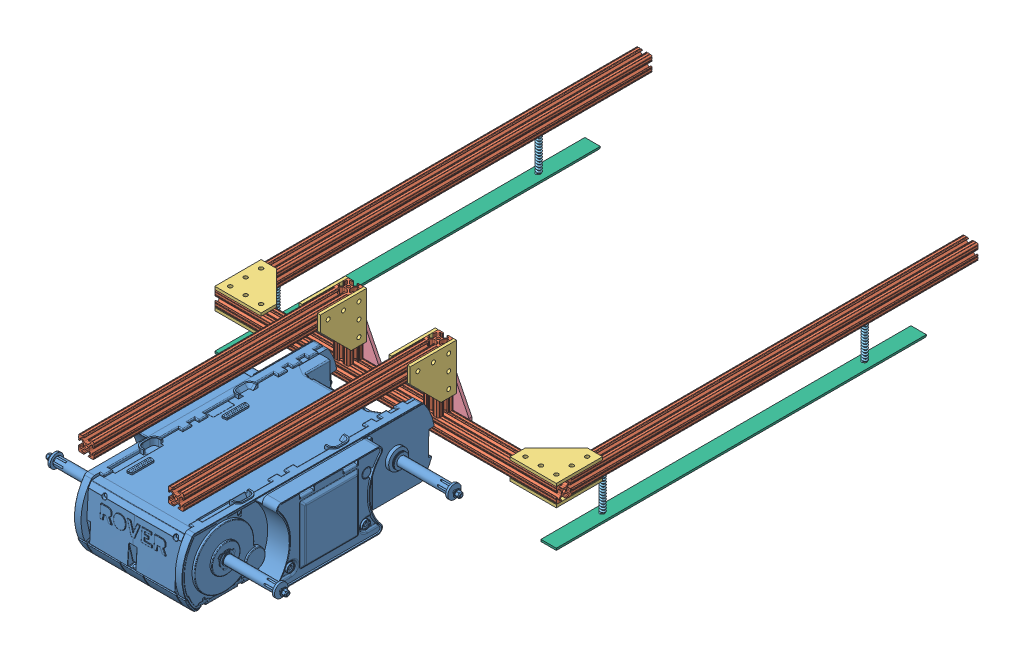
SolidWorks assembly BotAssembly.12.26.2020, configuration Default. Lengths in mm.
Overall size (562.5 192.5 1123.3).
26 component instances, 6 part files, 55 mates.
Components (placement in the parent):
- Rover Body-1: Rover Body [Default] at (125.1119 198.811 488.8206) size (400.01 131.58 418.13)
- Top Rail-10: Top Rail [Bot Mounting] at (51.1531 303.611 339.8706) size (25.4 25.4 419.1)
- Top Rail-12: Top Rail [Bot Mounting] at (199.0708 303.611 339.8706) size (25.4 25.4 419.1)
- Top Rail-13: Top Rail [Vertical Rail] at (51.1531 265.511 117.6206) x (1 0 0) z (0 1 0) size (25.4 25.4 101.6)
- Top Rail-15: Top Rail [Vertical Rail] at (199.0708 265.511 117.6206) x (1 0 0) z (0 1 0) size (25.4 25.4 101.6)
- Top Rail-14: Top Rail [Top Rail Base 16.3] at (125.1119 202.011 117.6206) x (0 1 0) z (-1 0 0) size (25.4 25.4 562.5)
- 47065T267_ALUMINUM T-SLOTTED FRAMING EXTRUSION-13: 47065T267_ALUMINUM T-SLOTTED FRAMING EXTRUSION [47065T267] at (36.0718 316.311 104.9206) x (0 0 1) z (1 0 0) size (76.2 76.2 4.76)
- 47065T267_ALUMINUM T-SLOTTED FRAMING EXTRUSION-9: 47065T267_ALUMINUM T-SLOTTED FRAMING EXTRUSION [47065T267] at (214.152 316.311 104.9206) x (0 0 1) z (1 0 0) size (76.2 76.2 4.76)
- Top Rail-11: Top Rail [Side Rail] at (393.6623 202.011 -229.71) size (25.4 25.4 669.26)
- Top Rail-16: Top Rail [Side Rail] at (-143.4384 202.011 -229.71) size (25.4 25.4 669.26)
- 47065T267_ALUMINUM T-SLOTTED FRAMING EXTRUSION-15: 47065T267_ALUMINUM T-SLOTTED FRAMING EXTRUSION [47065T267] at (406.3623 217.0923 130.3206) x (0 0 -1) z (0 1 0) size (76.2 76.2 4.76)
- 47065T267_ALUMINUM T-SLOTTED FRAMING EXTRUSION-14: 47065T267_ALUMINUM T-SLOTTED FRAMING EXTRUSION [47065T267] at (-156.1384 217.0923 130.3206) x (1 0 0) z (0 1 0) size (76.2 76.2 4.76)
- 47065T278_ALUMINUM T-SLOTTED FRAMING EXTRUSION-3: 47065T278_ALUMINUM T-SLOTTED FRAMING EXTRUSION [47065T278] at (160.9708 189.311 102.5393) size (76.2 76.2 4.76)
- 47065T278_ALUMINUM T-SLOTTED FRAMING EXTRUSION-4: 47065T278_ALUMINUM T-SLOTTED FRAMING EXTRUSION [47065T278] at (13.0531 189.311 102.5393) size (76.2 76.2 4.76)
- 47065T267_ALUMINUM T-SLOTTED FRAMING EXTRUSION-10: 47065T267_ALUMINUM T-SLOTTED FRAMING EXTRUSION [47065T267] at (406.3623 186.9298 130.3206) x (0 0 -1) z (0 1 0) size (76.2 76.2 4.76)
- 47065T267_ALUMINUM T-SLOTTED FRAMING EXTRUSION-12: 47065T267_ALUMINUM T-SLOTTED FRAMING EXTRUSION [47065T267] at (-156.1384 186.9298 130.3206) x (1 0 0) z (0 1 0) size (76.2 76.2 4.76)
- 47065T267_ALUMINUM T-SLOTTED FRAMING EXTRUSION-11: 47065T267_ALUMINUM T-SLOTTED FRAMING EXTRUSION [47065T267] at (66.2343 316.311 104.9206) x (0 0 1) z (1 0 0) size (76.2 76.2 4.76)
- 47065T267_ALUMINUM T-SLOTTED FRAMING EXTRUSION-16: 47065T267_ALUMINUM T-SLOTTED FRAMING EXTRUSION [47065T267] at (183.9895 316.311 104.9206) x (0 0 1) z (1 0 0) size (76.2 76.2 4.76)
- SkidAssembly.12.26.2020-1: SkidAssembly.12.26.2020 [Default] at (-122.0534 148.8468 -277.5557) x (-1 0 0) z (0 0 -1) size (25.4 67.77 609.6)
  - Rudimentary Spring-1: Rudimentary Spring [Default] at (21.385 -21.8607 112.8238) x (0.707107 0 0.707107) z (-0.707107 0 0.707107) size (9.2 66.86 9.2)
  - Skid Plate-1: Skid Plate [Default] at (8.685 -21.8607 178.1392) size (25.4 3.17 609.6)
  - Rudimentary Spring-2: Rudimentary Spring [Default] at (21.385 -21.8607 -318.9762) x (0.707107 0 0.707107) z (-0.707107 0 0.707107) size (9.2 66.86 9.2)
- SkidAssembly.12.26.2020-2: SkidAssembly.12.26.2020 [Default] at (415.0473 148.8468 -277.5557) x (-1 0 0) z (0 0 -1) size (25.4 67.77 609.6)
  - Rudimentary Spring-1: Rudimentary Spring [Default] at (21.385 -21.8607 112.8238) x (0.707107 0 0.707107) z (-0.707107 0 0.707107) size (9.2 66.86 9.2)
  - Skid Plate-1: Skid Plate [Default] at (8.685 -21.8607 178.1392) size (25.4 3.17 609.6)
  - Rudimentary Spring-2: Rudimentary Spring [Default] at (21.385 -21.8607 -318.9762) x (0.707107 0 0.707107) z (-0.707107 0 0.707107) size (9.2 66.86 9.2)
Mates (geometry in assembly coordinates):
- Distance1: distance = 38.1 mm anti-aligned: plane of Rover Body-1 through (214.1119 252.811 535.67) normal (0 1 0); plane of Top Rail-10 through (41.6027 290.911 549.4206) normal (0 -1 0)
- Distance2: distance = 38.1 mm anti-aligned: plane of Top Rail-12 through (189.5203 290.911 549.4206) normal (0 -1 0); plane of Rover Body-1 through (214.1119 252.811 535.67) normal (0 1 0)
- Distance4: distance = 9.525 mm: line of Top Rail-10 through (63.8531 294.0606 549.4206) axis (0 0 -1); plane of Rover Body-1 through (55.1119 249.071 259.3206) normal (0.999848 0.017452 0)
- Distance5: distance = 9.525 mm: line of Top Rail-12 through (186.3708 294.0606 549.4206) axis (0 0 -1); plane of Rover Body-1 through (195.1119 249.071 259.3206) normal (-0.999848 0.017452 0)
- Coincident14: coincident anti-aligned: plane of Top Rail-13 through (44.7367 214.711 127.0304) normal (0 -1 0); plane of Top Rail-14 through (-156.1384 214.711 127.171) normal (0 1 0)
- Coincident15: coincident aligned: plane of Top Rail-13 through (44.82 316.311 104.9206) normal (0 0 -1); plane of Top Rail-14 through (-156.1384 211.5614 104.9206) normal (0 0 -1)
- Width1: width aligned: plane of Top Rail-14 through (406.3623 195.5946 127.0304) normal (1 0 0); plane of Top Rail-15 through (-156.1384 195.5946 127.0304) normal (-1 0 0); plane of Top Rail-14 through (211.7708 316.311 111.2875) normal (1 0 0); plane of Top Rail-13 through (38.4531 316.311 108.0702) normal (-1 0 0)
- Coincident19: coincident: plane of Top Rail-13 through (41.6027 316.311 130.3206) normal (0 0 1)
- Coincident21: coincident aligned: plane of Top Rail-10 through (60.7035 316.311 549.4206) normal (0 1 0); plane of Top Rail-13 through (44.7367 316.311 127.0304) normal (0 1 0)
- Coincident22: coincident aligned: plane of Top Rail-10 through (38.4531 313.1614 549.4206) normal (-1 0 0); plane of Top Rail-13 through (38.4531 316.311 123.9536) normal (-1 0 0)
- Coincident23: coincident aligned: plane of Top Rail-12 through (211.7708 309.9441 549.4206) normal (1 0 0); plane of Top Rail-15 through (211.7708 316.311 127.171) normal (1 0 0)
- Coincident24: coincident aligned: plane of Top Rail-12 through (192.7377 316.311 549.4206) normal (0 1 0); plane of Top Rail-15 through (192.6544 316.311 127.0304) normal (0 1 0)
- Coincident25: coincident anti-aligned: plane of Top Rail-12 through (192.6544 294.2012 130.3206) normal (0 0 -1); plane of Top Rail-15 through (189.5203 316.311 130.3206) normal (0 0 1)
- Coincident26: coincident anti-aligned: plane of Top Rail-10 through (38.4531 313.1614 549.4206) normal (-1 0 0); plane of 47065T267_ALUMINUM T-SLOTTED FRAMING EXTRUSION-1 through (38.4531 316.311 104.9206) normal (1 0 0)
- Coincident28: coincident aligned: plane of Top Rail-13 through (44.7367 316.311 127.0304) normal (0 1 0); plane of 47065T267_ALUMINUM T-SLOTTED FRAMING EXTRUSION-1 through (38.4531 316.311 181.1206) normal (0 1 0)
- Coincident29: coincident aligned: plane of Top Rail-13 through (44.82 316.311 104.9206) normal (0 0 -1); plane of 47065T267_ALUMINUM T-SLOTTED FRAMING EXTRUSION-1 through (38.4531 316.311 104.9206) normal (0 0 -1)
- Coincident30: coincident anti-aligned: plane of Top Rail-12 through (211.7708 309.9441 549.4206) normal (1 0 0); plane of 47065T267_ALUMINUM T-SLOTTED FRAMING EXTRUSION-2 through (211.7708 316.311 104.9206) normal (-1 0 0)
- Coincident31: coincident aligned: plane of Top Rail-15 through (192.6544 316.311 127.0304) normal (0 1 0); plane of 47065T267_ALUMINUM T-SLOTTED FRAMING EXTRUSION-2 through (216.5333 316.311 181.1206) normal (0 1 0)
- Coincident32: coincident aligned: plane of Top Rail-15 through (208.6212 316.311 104.9206) normal (0 0 -1); plane of 47065T267_ALUMINUM T-SLOTTED FRAMING EXTRUSION-2 through (216.5333 316.311 104.9206) normal (0 0 -1)
- Coincident34: coincident aligned: plane of Top Rail-14 through (-156.1384 214.711 111.2875) normal (0 1 0); plane of Top Rail-16 through (-133.888 214.711 104.9206) normal (0 1 0)
- Coincident37: coincident aligned: plane of Top Rail-14 through (-156.1384 214.711 127.171) normal (0 1 0); plane of Top Rail-11 through (387.3292 214.711 104.9206) normal (0 1 0)
- Coincident39: coincident aligned: plane of Top Rail-11 through (406.3623 208.3441 104.9206) normal (1 0 0); plane of 47065T267_ALUMINUM T-SLOTTED FRAMING EXTRUSION-15 through (406.3623 219.4735 54.1206) normal (1 0 0)
- Coincident40: coincident anti-aligned: plane of Top Rail-11 through (403.2128 214.711 104.9206) normal (0 1 0); plane of 47065T267_ALUMINUM T-SLOTTED FRAMING EXTRUSION-15 through (406.3623 214.711 130.3206) normal (0 -1 0)
- Coincident42: coincident aligned: plane of Top Rail-16 through (-156.1384 211.5614 104.9206) normal (-1 0 0); plane of 47065T267_ALUMINUM T-SLOTTED FRAMING EXTRUSION-14 through (-156.1384 219.4735 130.3206) normal (-1 0 0)
- Coincident44: coincident anti-aligned: plane of Top Rail-16 through (-149.7716 214.711 104.9206) normal (0 1 0); plane of 47065T267_ALUMINUM T-SLOTTED FRAMING EXTRUSION-14 through (-156.1384 214.711 130.3206) normal (0 -1 0)
- Coincident45: coincident anti-aligned: plane of Top Rail-14 through (-156.1384 211.5614 104.9206) normal (0 0 -1); plane of 47065T278_ALUMINUM T-SLOTTED FRAMING EXTRUSION-1 through (160.9708 189.311 104.9206) normal (0 0 1)
- Coincident46: coincident anti-aligned: plane of Top Rail-14 through (-156.1384 211.5614 104.9206) normal (0 0 -1); plane of 47065T278_ALUMINUM T-SLOTTED FRAMING EXTRUSION-2 through (13.0531 189.311 104.9206) normal (0 0 1)
- Coincident47: coincident aligned: plane of Top Rail-14 through (-156.1384 189.311 108.0702) normal (0 -1 0); plane of 47065T278_ALUMINUM T-SLOTTED FRAMING EXTRUSION-1 through (237.1708 189.311 104.9206) normal (0 -1 0)
- Coincident48: coincident aligned: plane of Top Rail-14 through (-156.1384 189.311 108.0702) normal (0 -1 0); plane of 47065T278_ALUMINUM T-SLOTTED FRAMING EXTRUSION-2 through (89.2531 189.311 104.9206) normal (0 -1 0)
- Coincident53: coincident: line of 47065T267_ALUMINUM T-SLOTTED FRAMING EXTRUSION-2 through (211.7708 240.111 104.9206) axis (0 1 0); point of 47065T278_ALUMINUM T-SLOTTED FRAMING EXTRUSION-1
- Coincident54: coincident: line of 47065T267_ALUMINUM T-SLOTTED FRAMING EXTRUSION-1 through (38.4531 240.111 104.9206) axis (0 1 0); point of 47065T278_ALUMINUM T-SLOTTED FRAMING EXTRUSION-2
- Coincident55: coincident anti-aligned: plane of Top Rail-14 through (-156.1384 211.5614 104.9206) normal (0 0 -1); plane of Top Rail-16 through (-149.8549 192.6012 104.9206) normal (0 0 1)
- Coincident56: coincident aligned: plane of Top Rail-14 through (-156.1384 195.5946 127.0304) normal (-1 0 0); plane of Top Rail-16 through (-156.1384 211.5614 104.9206) normal (-1 0 0)
- Coincident57: coincident aligned: plane of Top Rail-14 through (-156.1384 208.3441 130.3206) normal (0 0 1); plane of 47065T267_ALUMINUM T-SLOTTED FRAMING EXTRUSION-14 through (-79.9384 219.4735 130.3206) normal (0 0 1)
- Coincident58: coincident anti-aligned: plane of Top Rail-14 through (-156.1384 211.5614 104.9206) normal (0 0 -1); plane of Top Rail-11 through (387.2459 192.6012 104.9206) normal (0 0 1)
- Coincident59: coincident aligned: plane of Top Rail-14 through (406.3623 195.5946 127.0304) normal (1 0 0); plane of Top Rail-11 through (406.3623 208.3441 104.9206) normal (1 0 0)
- Coincident60: coincident aligned: plane of Top Rail-14 through (-156.1384 208.3441 130.3206) normal (0 0 1); plane of 47065T267_ALUMINUM T-SLOTTED FRAMING EXTRUSION-15 through (406.3623 219.4735 130.3206) normal (0 0 1)
- Coincident61: coincident aligned: plane of 47065T267_ALUMINUM T-SLOTTED FRAMING EXTRUSION-14 through (-156.1384 219.4735 130.3206) normal (-1 0 0); plane of 47065T267_ALUMINUM T-SLOTTED FRAMING EXTRUSION-12 through (-156.1384 189.311 130.3206) normal (-1 0 0)
- Coincident62: coincident aligned: plane of 47065T267_ALUMINUM T-SLOTTED FRAMING EXTRUSION-14 through (-79.9384 219.4735 130.3206) normal (0 0 1); plane of 47065T267_ALUMINUM T-SLOTTED FRAMING EXTRUSION-12 through (-79.9384 189.311 130.3206) normal (0 0 1)
- Distance6: distance = 25.4 mm anti-aligned: plane of 47065T267_ALUMINUM T-SLOTTED FRAMING EXTRUSION-6 through (-156.1384 189.311 130.3206) normal (0 1 0); plane of 47065T267_ALUMINUM T-SLOTTED FRAMING EXTRUSION-4 through (-156.1384 214.711 130.3206) normal (0 -1 0)
- Distance7: distance = 25.4 mm anti-aligned: plane of 47065T267_ALUMINUM T-SLOTTED FRAMING EXTRUSION-3 through (406.3623 214.711 130.3206) normal (0 -1 0); plane of 47065T267_ALUMINUM T-SLOTTED FRAMING EXTRUSION-5 through (406.3623 189.311 130.3206) normal (0 1 0)
- Coincident63: coincident aligned: plane of 47065T267_ALUMINUM T-SLOTTED FRAMING EXTRUSION-15 through (406.3623 219.4735 54.1206) normal (1 0 0); plane of 47065T267_ALUMINUM T-SLOTTED FRAMING EXTRUSION-10 through (406.3623 189.311 54.1206) normal (1 0 0)
- Coincident64: coincident aligned: plane of 47065T267_ALUMINUM T-SLOTTED FRAMING EXTRUSION-15 through (406.3623 219.4735 130.3206) normal (0 0 1); plane of 47065T267_ALUMINUM T-SLOTTED FRAMING EXTRUSION-10 through (406.3623 189.311 130.3206) normal (0 0 1)
- Coincident65: coincident aligned: plane of 47065T267_ALUMINUM T-SLOTTED FRAMING EXTRUSION-2 through (216.5333 316.311 181.1206) normal (0 1 0); plane of 47065T267_ALUMINUM T-SLOTTED FRAMING EXTRUSION-8 through (186.3708 316.311 181.1206) normal (0 1 0)
- Coincident66: coincident aligned: plane of 47065T267_ALUMINUM T-SLOTTED FRAMING EXTRUSION-1 through (38.4531 316.311 181.1206) normal (0 1 0); plane of 47065T267_ALUMINUM T-SLOTTED FRAMING EXTRUSION-7 through (68.6156 316.311 181.1206) normal (0 1 0)
- Coincident67: coincident aligned: plane of 47065T267_ALUMINUM T-SLOTTED FRAMING EXTRUSION-1 through (38.4531 290.911 181.1206) normal (0 0 1); plane of 47065T267_ALUMINUM T-SLOTTED FRAMING EXTRUSION-7 through (68.6156 290.911 181.1206) normal (0 0 1)
- Coincident68: coincident aligned: plane of 47065T267_ALUMINUM T-SLOTTED FRAMING EXTRUSION-2 through (216.5333 290.911 181.1206) normal (0 0 1); plane of 47065T267_ALUMINUM T-SLOTTED FRAMING EXTRUSION-8 through (186.3708 290.911 181.1206) normal (0 0 1)
- Coincident69: coincident anti-aligned: plane of Top Rail-13 through (63.8531 316.311 111.2875) normal (1 0 0); plane of 47065T267_ALUMINUM T-SLOTTED FRAMING EXTRUSION-7 through (63.8531 316.311 104.9206) normal (-1 0 0)
- Coincident70: coincident anti-aligned: plane of Top Rail-15 through (186.3708 316.311 108.0702) normal (-1 0 0); plane of 47065T267_ALUMINUM T-SLOTTED FRAMING EXTRUSION-8 through (186.3708 316.311 104.9206) normal (1 0 0)
- Concentric2: concentric aligned: cylinder of Top Rail-16 through (-143.4384 189.311 41.4206) axis (0 1 0) radius 3.175; cylinder of SkidAssembly.12.26.2020-1/Skid Plate-1 through (-143.4384 123.8111 41.4206) axis (0 1 0) radius 3.175
- Coincident71: coincident anti-aligned: plane of Top Rail-16 through (-137.1053 189.311 104.9206) normal (0 -1 0); plane of SkidAssembly.12.26.2020-1/Rudimentary Spring-1 through (-132.932 189.311 -394.378) normal (0 1 0)
- Coincident72: coincident aligned: plane of SkidAssembly.12.26.2020-1/Skid Plate-1 through (-156.1384 126.9861 130.3206) normal (0 0 1); plane of SkidAssembly.12.26.2020-2/Skid Plate-1 through (380.9623 126.9861 130.3206) normal (0 0 1)
- Coincident73: coincident aligned: plane of SkidAssembly.12.26.2020-1/Skid Plate-1 through (-156.1384 126.9861 -479.2794) normal (0 1 0); plane of SkidAssembly.12.26.2020-2/Skid Plate-1 through (380.9623 126.9861 -479.2794) normal (0 1 0)
- Coincident74: coincident aligned: plane of 47065T267_ALUMINUM T-SLOTTED FRAMING EXTRUSION-10 through (406.3623 189.311 54.1206) normal (1 0 0); plane of SkidAssembly.12.26.2020-2/Skid Plate-1 through (406.3623 126.9861 -476.5298) normal (1 0 0)
- Coincident75: coincident aligned: plane of Top Rail-10 through (44.7367 294.2012 130.3206) normal (0 0 -1); plane of Top Rail-12 through (192.6544 294.2012 130.3206) normal (0 0 -1)
